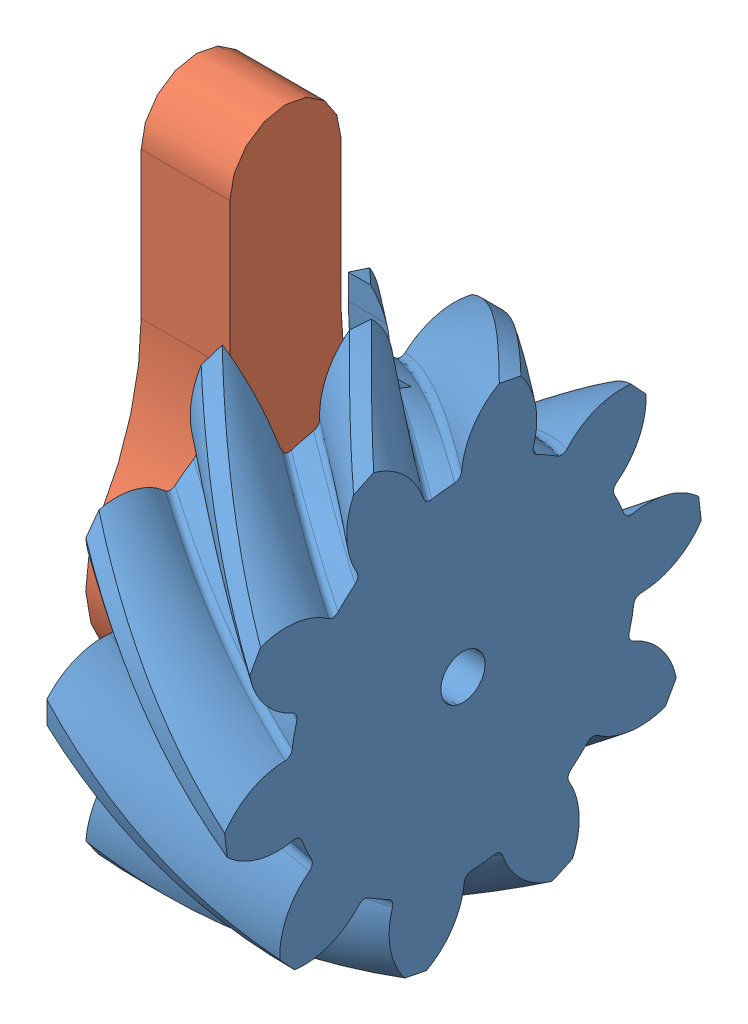
SolidWorks assembly Assem1, configuration Default. Lengths in mm.
Overall size (18 82 82).
2 component instances, 2 part files, 2 mates.
Components (placement in the parent):
- small gear-1: small gear [ISO - RH Helical gear 2M 10T 45HA 20PA 12FW ---10A75H50L3.0N] at (-29.465 2.662 10.5737) size (12 43.71 32.41)
- servo arm-1: servo arm [Default] at (-29.465 2.662 10.5737) x (0 0 1) z (-1 0 0) size (15 35 6)
Mates (geometry in assembly coordinates):
- Coincident1: coincident anti-aligned: line of small gear-1 through (-17.465 2.662 10.5737) axis (-1 0 0); line of servo arm-1 through (-35.465 2.662 10.5737) axis (1 0 0)
- Coincident2: coincident anti-aligned: plane of small gear-1 through (-29.465 2.662 10.5737) normal (-1 0 0); plane of servo arm-1 through (-29.465 26.412 10.5737) normal (1 0 0)
